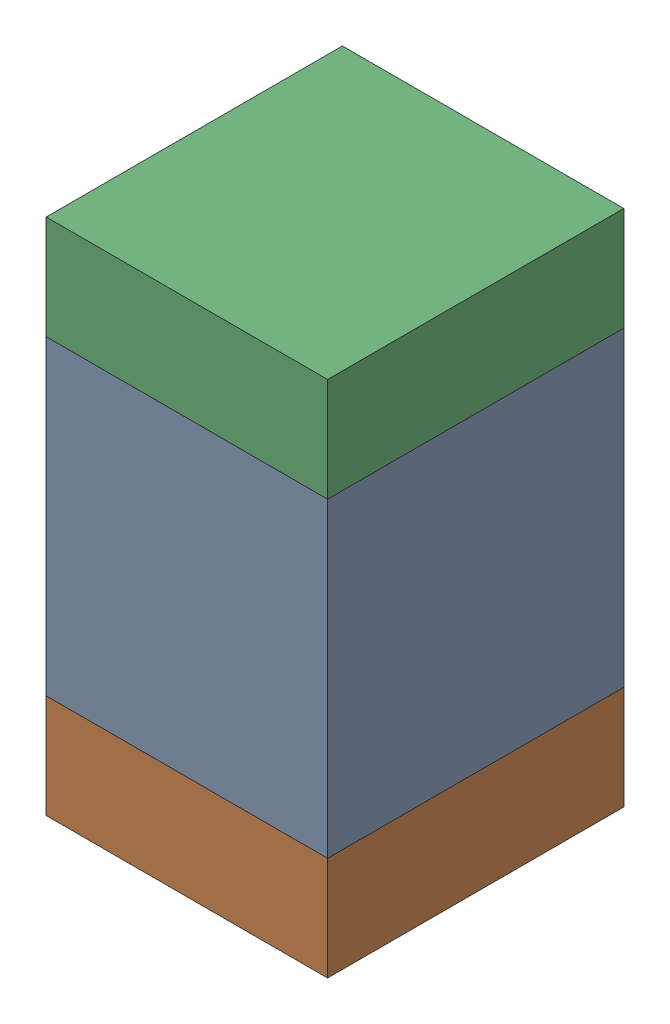
SolidWorks assembly C9, configuration Default. Lengths in mm.
Overall size (0.95 1.75 1).
6 component instances, 2 part files, 0 mates.
Components (placement in the parent):
- 959208528-1: 959208528 [Default] at (108.577 76.835 0) size (0.95 1.05 1)
  - Extruded-15-1: Extruded-15 [Default] at origin size (0.95 1.05 1)
- 959208664-1: 959208664 [Default] at (108.577 76.135 0) size (0.95 0.35 1)
  - Extruded-14-1: Extruded-14 [Default] at origin size (0.95 0.35 1)
- 959208664-2: 959208664 [Default] at (108.577 77.535 0) size (0.95 0.35 1)
  - Extruded-14-1: Extruded-14 [Default] at origin size (0.95 0.35 1)
